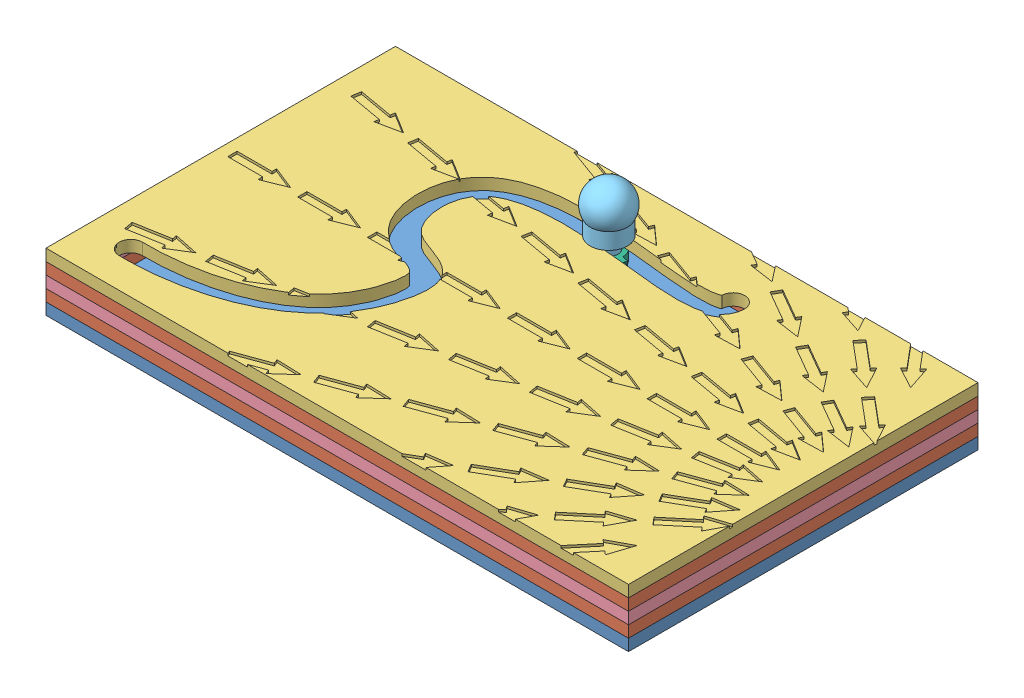
SolidWorks assembly line integral model, configuration Default. Lengths in mm.
Overall size (250 45.77 150).
7 component instances, 6 part files, 13 mates.
Components (placement in the parent):
- base1-1: base1 [Default] at (-67.6694 132.594 282.7408) size (250 5 150)
- base2_1-1: base2_1 [Default] at (-67.6694 137.594 282.7408) size (250 5 150)
- base2_1-2: base2_1 [Default] at (-67.6694 147.594 282.7408) size (250 5 150)
- base3 - Copy-1: base3 - Copy [Default] at (182.3306 152.594 132.7408) x (-1 0 0) z (0 0 -1) size (250 5 150)
- base2-3: base2 [Default] at (-67.6694 142.594 282.7408) size (250 5 150)
- slider - Copy-1: slider - Copy [Default] at (48.3434 145.594 157.1967) x (0.962261 0 -0.272127) z (0.272127 0 0.962261) size (18.42 32.77 18.42)
- washer clip - Copy-1: washer clip - Copy [Default] at (48.3434 147.594 157.1967) x (-0.973455 0 -0.228877) z (0.228877 0 -0.973455) size (14.5 5 12)
Mates (geometry in assembly coordinates):
- Coincident14: coincident aligned: line of base2_1-2 through (182.3306 152.594 282.7408) axis (0 0 -1); line of base3 - Copy-1 through (182.3306 152.594 282.7408) axis (0 0 -1)
- Coincident15: coincident aligned: line of base2_1-2 through (-67.6694 152.594 132.7408) axis (0 0 1); line of base3 - Copy-1 through (-67.6694 152.594 132.7408) axis (0 0 1)
- Coincident16: coincident aligned: line of base2_1-2 through (182.3306 152.594 132.7408) axis (-1 0 0); line of base3 - Copy-1 through (182.3306 152.594 132.7408) axis (-1 0 0)
- Coincident18: coincident aligned: line of base1-1 through (182.3306 137.594 282.7408) axis (0 0 -1); line of base2_1-1 through (182.3306 137.594 282.7408) axis (0 0 -1)
- Coincident19: coincident aligned: line of base1-1 through (182.3306 137.594 132.7408) axis (-1 0 0); line of base2_1-1 through (182.3306 137.594 132.7408) axis (-1 0 0)
- Coincident20: coincident aligned: line of base2_1-1 through (182.3306 142.594 282.7408) axis (0 0 -1); line of base2-3 through (182.3306 142.594 282.7408) axis (0 0 -1)
- Coincident21: coincident aligned: line of base2_1-1 through (182.3306 142.594 132.7408) axis (-1 0 0); line of base2-3 through (182.3306 142.594 132.7408) axis (-1 0 0)
- Coincident22: coincident aligned: line of base2_1-2 through (182.3306 147.594 132.7408) axis (-1 0 0); line of base2-3 through (182.3306 147.594 132.7408) axis (-1 0 0)
- Coincident23: coincident aligned: line of base2_1-2 through (182.3306 147.594 282.7408) axis (0 0 -1); line of base2-3 through (182.3306 147.594 282.7408) axis (0 0 -1)
- Coincident24: coincident anti-aligned: plane of base3 - Copy-1 through (182.3306 152.594 132.7408) normal (0 -1 0); plane of washer clip - Copy-1 through (48.3434 152.594 157.1967) normal (0 1 0)
- Concentric1: concentric aligned: cylinder of slider - Copy-1 through (48.3434 157.594 157.1967) axis (0 -1 0) radius 4; cylinder of washer clip - Copy-1 through (48.3434 152.594 157.1967) axis (0 -1 0) radius 4
- Tangent1: tangent: face of base3 - Copy-1; cylinder of slider - Copy-1 through (48.3434 157.594 157.1967) axis (0 -1 0) radius 4
- Coincident25: coincident anti-aligned: plane of base3 - Copy-1 through (182.3306 157.594 132.7408) normal (0 1 0); plane of slider - Copy-1 through (48.3434 157.594 157.1967) normal (0 -1 0)
